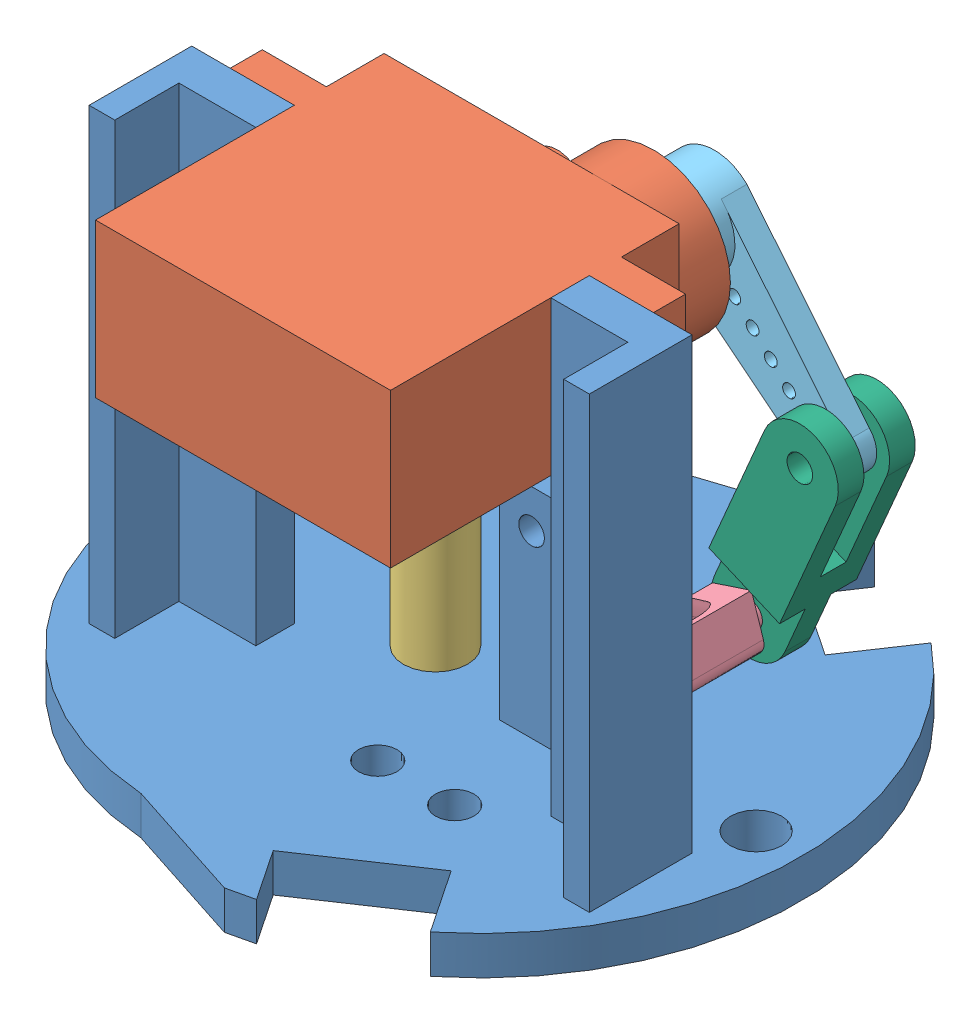
SolidWorks assembly Rückseite, configuration Standard. Lengths in mm.
Overall size (50 47.45 49.14).
6 component instances, 6 part files, 13 mates.
Components (placement in the parent):
- Backside-1: Backside [Standard] at (-0.7502 -6.4244 50) size (50 38 49.14)
- servo-1: servo [Standard] at (-7.7502 31.5756 69.5) x (1 0 0) z (0 1 0) size (33 29.25 12)
- Drücker-1: Drücker [Standard] at (-2.5879 -15.8748 21.7522) size (5 34 5)
- Hebel-1: Hebel [Standard] at (9.2498 10.5756 49) x (0.892651 -0.450748 0) z (0 0 1) size (28.07 10.32 14)
- Servo-Arm-1: Servo-Arm [Standard] at (9.2498 25.5756 38.25) x (0.710639 -0.703557 0) z (-0.703557 -0.710639 0) size (20.6 4.3 7.2)
- Hebel2-1: Hebel2 [Standard] at (13.9954 1.2373 38.25) x (0.394267 0.918996 0) z (0.918996 -0.394267 0) size (21 6 6)
Mates (geometry in assembly coordinates):
- Konzentrisch1: concentric aligned: cylinder of Drücker-1 through (-0.7502 18.1252 50) axis (0 -1 0) radius 2.5; cylinder of Backside-1 through (-0.7502 -3.4244 50) axis (0 -1 0) radius 2.5
- Konzentrisch2: concentric anti-aligned: cylinder of Backside-1 through (9.2498 10.5756 42.5) axis (0 0 1) radius 1; cylinder of Hebel-1 through (9.2498 10.5756 51) axis (0 0 -1) radius 1
- Deckungsgleich1: coincident anti-aligned: plane of Backside-1 through (6.7498 13.5756 51) normal (0 0 -1); plane of Hebel-1 through (9.2498 10.5756 51) normal (0 0 1)
- Parallel1: parallel anti-aligned: plane of Drücker-1 through (-3.7502 10.1252 49) normal (0 0 1); plane of Hebel-1 through (9.2498 10.5756 49) normal (0 0 -1)
- Tangential1: tangent anti-aligned: cylinder of Drücker-1 through (-0.7502 15.6252 46) axis (0 0 1) radius 1; plane of Hebel-1 through (8.7991 9.683 51) normal (0.450748 0.892651 0)
- Konzentrisch3: concentric anti-aligned: cylinder of servo-1 through (9.2498 25.5756 43) axis (0 0 1) radius 6; cylinder of Servo-Arm-1 through (9.2498 25.5756 42.55) axis (0 0 -1) radius 2.25
- Deckungsgleich6: coincident anti-aligned: plane of Backside-1 through (-7.7502 31.5756 57) normal (1 0 0); plane of servo-1 through (-7.7502 31.5756 47) normal (-1 0 0)
- Deckungsgleich7: coincident anti-aligned: plane of Backside-1 through (-7.7502 31.5756 54) normal (0 0 -1); plane of servo-1 through (20.2498 31.5756 54) normal (0 0 1)
- Deckungsgleich11: coincident aligned: plane of Backside-1 through (-0.7502 31.5756 50) normal (0 1 0); plane of servo-1 through (-7.7502 31.5756 47) normal (0 1 0)
- Deckungsgleich9: coincident anti-aligned: plane of Servo-Arm-1 through (9.2498 25.5756 38.25) normal (0 0 -1); plane of Hebel2-1 through (13.9954 1.2373 38.25) normal (0 0 1)
- Deckungsgleich10: coincident anti-aligned: circle of Servo-Arm-1; cylinder of Hebel2-1 through (19.9094 15.0223 40.25) axis (0 0 -1) radius 1
- Konzentrisch4: concentric anti-aligned: cylinder of Hebel-1 through (13.9954 1.2373 37) axis (0 0 1) radius 1; cylinder of Hebel2-1 through (13.9954 1.2373 40.25) axis (0 0 -1) radius 1
- Deckungsgleich12: coincident anti-aligned: plane of servo-1 through (9.2498 25.5756 40.25) normal (0 0 -1); plane of Servo-Arm-1 through (9.2498 25.5756 40.25) normal (0 0 1)
